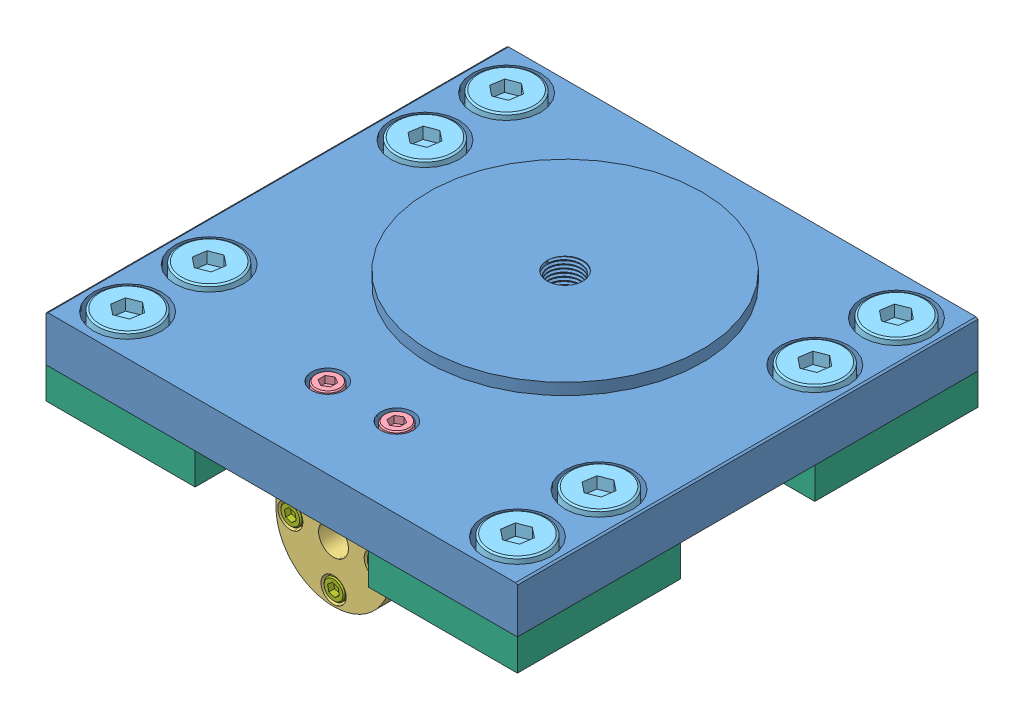
SolidWorks assembly carriage_assembly, configuration Default. Lengths in mm.
Overall size (104 39.96 101.6).
25 component instances, 8 part files, 45 mates.
Components (placement in the parent):
- carriage-2: carriage [Default] at (31.9394 97.9973 42.1985) size (104 12.7 101.6)
- backlash_nut-1: backlash_nut [Default] at (-20.0606 84.7893 18.0685) x (-1 0 0) z (0 0 -1) size (25.22 25.22 25.4)
- backlash_mount-1: backlash_mount [Default] at (-20.0606 84.7893 18.0685) size (25.4 25.91 12.7)
- S-006-075-SKT-H-SS-1: S-006-075-SKT-H-SS [Default] at (-27.6806 104.6521 24.4185) size (5.74 22.92 5.74)
- S-006-075-SKT-H-SS-2: S-006-075-SKT-H-SS [Default] at (-12.4406 104.6521 24.4185) size (5.74 22.92 5.74)
- M-080-160-SKT-H-SS-1: M-080-160-SKT-H-SS [Default] at (-63.0606 103.7573 -50.4015) x (-1 0 0) z (0 1 0) size (13 13 21.41)
- M-080-160-SKT-H-SS-9: M-080-160-SKT-H-SS [Default] at (-63.0606 103.7573 -32.4015) x (-1 0 0) z (0 1 0) size (13 13 21.41)
- M-080-160-SKT-H-SS-11: M-080-160-SKT-H-SS [Default] at (-63.0606 103.7573 15.1985) x (-1 0 0) z (0 1 0) size (13 13 21.41)
- M-080-160-SKT-H-SS-13: M-080-160-SKT-H-SS [Default] at (-63.0606 103.7573 33.1985) x (-1 0 0) z (0 1 0) size (13 13 21.41)
- M-080-160-SKT-H-SS-14: M-080-160-SKT-H-SS [Default] at (22.9394 103.7573 33.1985) x (-1 0 0) z (0 1 0) size (13 13 21.41)
- M-080-160-SKT-H-SS-12: M-080-160-SKT-H-SS [Default] at (22.9394 103.7573 15.1985) x (-1 0 0) z (0 1 0) size (13 13 21.41)
- M-080-160-SKT-H-SS-10: M-080-160-SKT-H-SS [Default] at (22.9394 103.7573 -32.4015) x (-1 0 0) z (0 1 0) size (13 13 21.41)
- M-080-160-SKT-H-SS-8: M-080-160-SKT-H-SS [Default] at (22.9394 103.7573 -50.4015) x (-1 0 0) z (0 1 0) size (13 13 21.41)
- spacer-1: spacer [Default] at (-55.6106 91.0773 -41.4015) x (1 0 0) z (0 1 0) size (32.9 36 6.92)
- spacer-2: spacer [Default] at (-55.6106 91.0773 24.1985) x (1 0 0) z (0 1 0) size (32.9 36 6.92)
- S-004-075-SKT-H-SS-1: S-004-075-SKT-H-SS [Default] at (-29.5856 84.7893 27.9237) size (4.65 4.65 22.21)
- S-004-075-SKT-H-SS-2: S-004-075-SKT-H-SS [Default] at (-20.0606 75.2643 27.9237) size (4.65 4.65 22.21)
- S-004-075-SKT-H-SS-3: S-004-075-SKT-H-SS [Default] at (-10.5356 84.7893 27.9237) size (4.65 4.65 22.21)
- S-004-075-SKT-H-SS-4: S-004-075-SKT-H-SS [Default] at (-20.0606 94.3143 27.9237) size (4.65 4.65 22.21)
- S-004-025-NUT-SS-1: S-004-025-NUT-SS [Default] at (-29.5856 84.7893 9.3373) x (0.954077 -0.299562 0) z (0 0 1) size (7.56 7.64 2.68)
- S-004-025-NUT-SS-2: S-004-025-NUT-SS [Default] at (-20.0606 94.3143 9.3373) x (0.21761 -0.976036 0) z (0 0 1) size (7.56 7.64 2.68)
- S-004-025-NUT-SS-3: S-004-025-NUT-SS [Default] at (-20.0606 75.2643 9.3373) x (0.21761 -0.976036 0) z (0 0 1) size (7.56 7.64 2.68)
- S-004-025-NUT-SS-4: S-004-025-NUT-SS [Default] at (-10.5356 84.7893 9.3373) x (0.954077 -0.299562 0) z (0 0 1) size (7.56 7.64 2.68)
- spacer-3: spacer [Default] at (15.4894 97.9973 24.1985) x (-1 0 0) z (0 -1 0) size (32.9 36 6.92)
- spacer-4: spacer [Default] at (15.4894 97.9973 -41.4015) x (-1 0 0) z (0 -1 0) size (32.9 36 6.92)
Mates (geometry in assembly coordinates):
- Concentric1: concentric aligned: circle of carriage-2; circle of backlash_mount-1
- Concentric2: concentric aligned: circle of carriage-2; circle of backlash_mount-1
- Coincident1: coincident anti-aligned: plane of carriage-2 through (31.9394 97.9973 42.1985) normal (0 -1 0); plane of backlash_mount-1 through (-32.7606 97.9973 30.7685) normal (0 1 0)
- Concentric3: concentric anti-aligned: circle of backlash_nut-1; circle of backlash_mount-1
- Concentric4: concentric aligned: circle of backlash_nut-1; circle of backlash_mount-1
- Coincident3: coincident anti-aligned: plane of backlash_nut-1 through (-20.0606 84.7893 18.0685) normal (0 0 1); plane of backlash_mount-1 through (-20.0606 84.7893 18.0685) normal (0 0 -1)
- Concentric5: concentric anti-aligned: circle of carriage-2; circle of S-006-075-SKT-H-SS-1
- Coincident4: coincident anti-aligned: plane of carriage-2 through (-25.782 104.6521 24.4185) normal (0 1 0); plane of S-006-075-SKT-H-SS-1 through (-27.6806 104.6521 24.4185) normal (0 -1 0)
- Concentric6: concentric aligned: circle of carriage-2; circle of M-080-160-SKT-H-SS-1
- Coincident5: coincident anti-aligned: plane of carriage-2 through (-58.8606 103.7573 -50.4015) normal (0 1 0); plane of M-080-160-SKT-H-SS-1 through (-63.0606 103.7573 -50.4015) normal (0 -1 0)
- Concentric7: concentric anti-aligned: circle of carriage-2; circle of M-080-160-SKT-H-SS-9
- Concentric8: concentric anti-aligned: circle of carriage-2; circle of M-080-160-SKT-H-SS-11
- Concentric9: concentric anti-aligned: circle of carriage-2; circle of M-080-160-SKT-H-SS-13
- Coincident6: coincident anti-aligned: plane of carriage-2 through (-58.8606 103.7573 -32.4015) normal (0 1 0); plane of M-080-160-SKT-H-SS-9 through (-63.0606 103.7573 -32.4015) normal (0 -1 0)
- Coincident7: coincident anti-aligned: plane of carriage-2 through (-58.8606 103.7573 15.1985) normal (0 1 0); plane of M-080-160-SKT-H-SS-11 through (-63.0606 103.7573 15.1985) normal (0 -1 0)
- Coincident8: coincident anti-aligned: plane of carriage-2 through (-58.8606 103.7573 33.1985) normal (0 1 0); plane of M-080-160-SKT-H-SS-13 through (-63.0606 103.7573 33.1985) normal (0 -1 0)
- Coincident9: coincident aligned: plane of carriage-2 through (-72.0606 108.1573 -59.4015) normal (-1 0 0); plane of spacer-1 through (-72.0606 97.9973 -23.4015) normal (-1 0 0)
- Coincident11: coincident anti-aligned: plane of carriage-2 through (31.9394 97.9973 42.1985) normal (0 -1 0); plane of spacer-1 through (-55.6106 97.9973 -41.4015) normal (0 1 0)
- Coincident12: coincident aligned: plane of carriage-2 through (-72.0606 108.1573 -59.4015) normal (0 0 -1); plane of spacer-1 through (-72.0606 97.9973 -59.4015) normal (0 0 -1)
- Concentric10: concentric aligned: circle of carriage-2; circle of spacer-2
- Coincident13: coincident aligned: plane of carriage-2 through (-72.0606 108.1573 42.1985) normal (0 0 1); plane of spacer-2 through (-72.0606 97.9973 42.1985) normal (0 0 1)
- Concentric11: concentric aligned: circle of carriage-2; circle of spacer-2
- Coincident15: coincident anti-aligned: plane of carriage-2 through (31.9394 97.9973 42.1985) normal (0 -1 0); plane of spacer-2 through (-55.6106 97.9973 24.1985) normal (0 1 0)
- Concentric12: concentric anti-aligned: circle of backlash_mount-1; circle of S-004-075-SKT-H-SS-1
- Coincident16: coincident anti-aligned: plane of backlash_mount-1 through (-27.9537 84.7893 27.9237) normal (0 0 1); plane of S-004-075-SKT-H-SS-1 through (-29.5856 84.7893 27.9237) normal (0 0 -1)
- Concentric13: concentric aligned: circle of backlash_mount-1; circle of S-004-075-SKT-H-SS-2
- Concentric14: concentric aligned: circle of backlash_mount-1; circle of S-004-075-SKT-H-SS-3
- Concentric15: concentric anti-aligned: circle of backlash_mount-1; circle of S-004-075-SKT-H-SS-4
- Coincident17: coincident anti-aligned: plane of backlash_mount-1 through (-8.9037 84.7893 27.9237) normal (0 0 1); plane of S-004-075-SKT-H-SS-3 through (-10.5356 84.7893 27.9237) normal (0 0 -1)
- Coincident18: coincident anti-aligned: plane of backlash_mount-1 through (-18.4287 75.2643 27.9237) normal (0 0 1); plane of S-004-075-SKT-H-SS-2 through (-20.0606 75.2643 27.9237) normal (0 0 -1)
- Coincident19: coincident anti-aligned: plane of backlash_mount-1 through (-18.4287 94.3143 27.9237) normal (0 0 1); plane of S-004-075-SKT-H-SS-4 through (-20.0606 94.3143 27.9237) normal (0 0 -1)
- Concentric16: concentric aligned: circle of backlash_nut-1; circle of ?
- Coincident20: coincident anti-aligned: plane of backlash_nut-1 through (-20.0606 84.7893 11.7185) normal (0 0 -1); plane of ? through (-10.5356 84.7893 11.7185) normal (0 0 1)
- Concentric17: concentric aligned: circle of backlash_nut-1; circle of S-004-025-NUT-SS-1
- Coincident21: coincident anti-aligned: plane of backlash_nut-1 through (-20.0606 84.7893 11.7185) normal (0 0 -1); plane of S-004-025-NUT-SS-1 through (-29.5856 84.7893 11.7185) normal (0 0 1)
- Concentric18: concentric anti-aligned: circle of backlash_nut-1; circle of S-004-025-NUT-SS-2
- Coincident22: coincident anti-aligned: plane of backlash_nut-1 through (-20.0606 84.7893 11.7185) normal (0 0 -1); plane of S-004-025-NUT-SS-2 through (-20.0606 94.3143 11.7185) normal (0 0 1)
- Parallel1: parallel anti-aligned: plane of carriage-2 through (31.9394 97.9973 42.1985) normal (0 -1 0); plane of S-004-025-NUT-SS-1 through (-27.7525 87.9643 11.7185) normal (0 1 0)
- Parallel2: parallel anti-aligned: plane of carriage-2 through (31.9394 97.9973 42.1985) normal (0 -1 0); plane of S-004-025-NUT-SS-2 through (-18.2275 97.4893 11.7185) normal (0 1 0)
- Concentric19: concentric anti-aligned: circle of carriage-2; cylinder of spacer-3 through (22.9394 91.0773 33.1985) axis (0 -1 0) radius 4.2
- Concentric20: concentric anti-aligned: circle of carriage-2; circle of spacer-3
- Coincident25: coincident anti-aligned: plane of carriage-2 through (31.9394 97.9973 42.1985) normal (0 -1 0); plane of spacer-3 through (15.4894 97.9973 24.1985) normal (0 1 0)
- Concentric21: concentric anti-aligned: circle of carriage-2; cylinder of spacer-4 through (22.9394 91.0773 -50.4015) axis (0 -1 0) radius 4.2
- Concentric22: concentric anti-aligned: circle of carriage-2; circle of spacer-4
- Coincident29: coincident anti-aligned: plane of carriage-2 through (31.9394 97.9973 42.1985) normal (0 -1 0); plane of spacer-4 through (15.4894 97.9973 -41.4015) normal (0 1 0)
